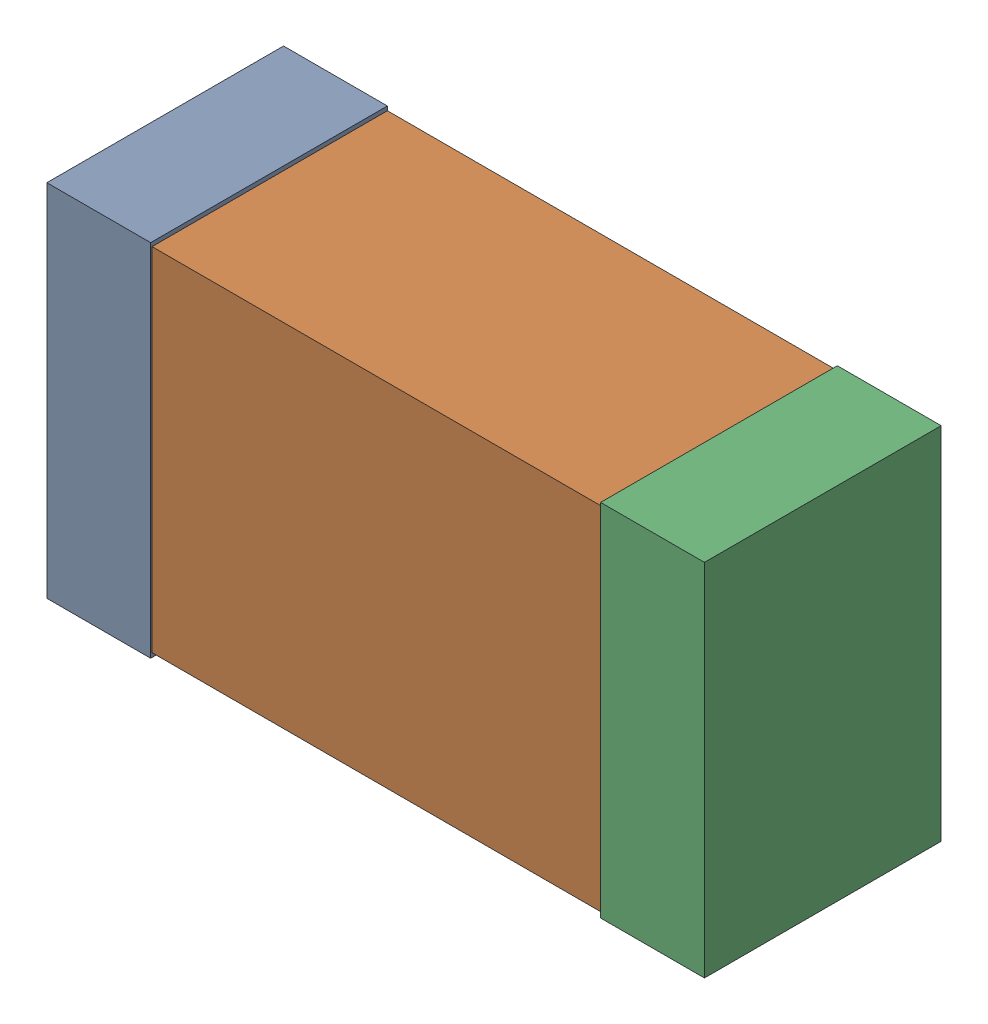
SolidWorks assembly C13_Motor_8Kanaloa_v2.0.0_Motor, configuration Default. Lengths in mm.
Overall size (2.38 1.3 0.85).
6 component instances, 2 part files, 0 mates.
Components (placement in the parent):
- 352877648-1: 352877648 [Default] at (145.046 142.367 0) size (0.38 1.3 0.85)
  - Extruded_14-1: Extruded_14 [Default] at origin size (0.38 1.3 0.85)
- 352877392-1: 352877392 [Default] at (146.046 142.367 0) size (2.2 1.27 0.85)
  - Extruded_15-1: Extruded_15 [Default] at origin size (2.2 1.27 0.85)
- 352877648-2: 352877648 [Default] at (147.046 142.367 0) size (0.38 1.3 0.85)
  - Extruded_14-1: Extruded_14 [Default] at origin size (0.38 1.3 0.85)
